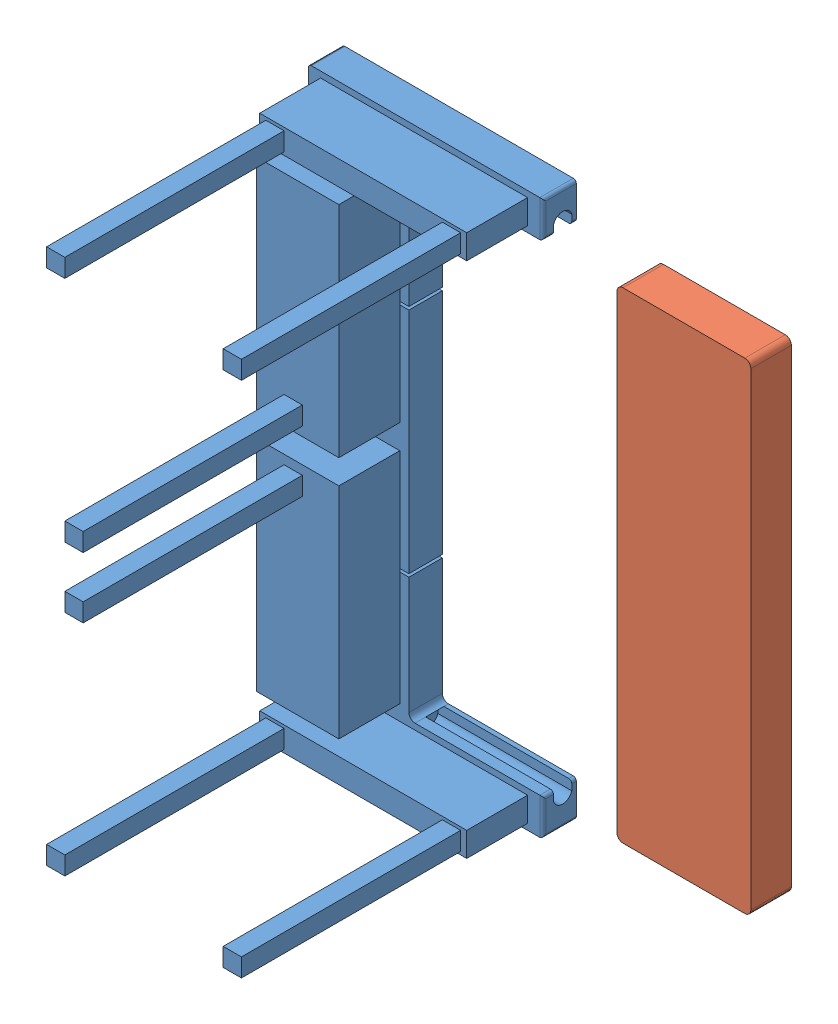
SolidWorks assembly Assem1, configuration Default. Lengths in mm.
Overall size (1845.75 2311.4 1337.45).
2 component instances, 2 part files, 2 mates.
Components (placement in the parent):
- Bed Matt-1: Bed Matt [Default] at (-1383.327 1114.1613 -26.982) size (977.9 2311.4 1308.1)
- Strecher-1: Strecher [Default] at (-96.3778 961.7613 45.268) size (558.8 2006.6 169.05)
Mates (geometry in assembly coordinates):
- Coincident1: coincident aligned: plane of Bed Matt-1 through (-1383.327 1114.1613 214.318) normal (0 0 1); plane of Strecher-1 through (-70.9778 -1019.4387 214.318) normal (0 0 1)
- Coincident2: coincident anti-aligned: plane of Bed Matt-1 through (-405.427 961.7613 214.318) normal (0 -1 0); plane of Strecher-1 through (-70.9778 961.7613 214.318) normal (0 1 0)
